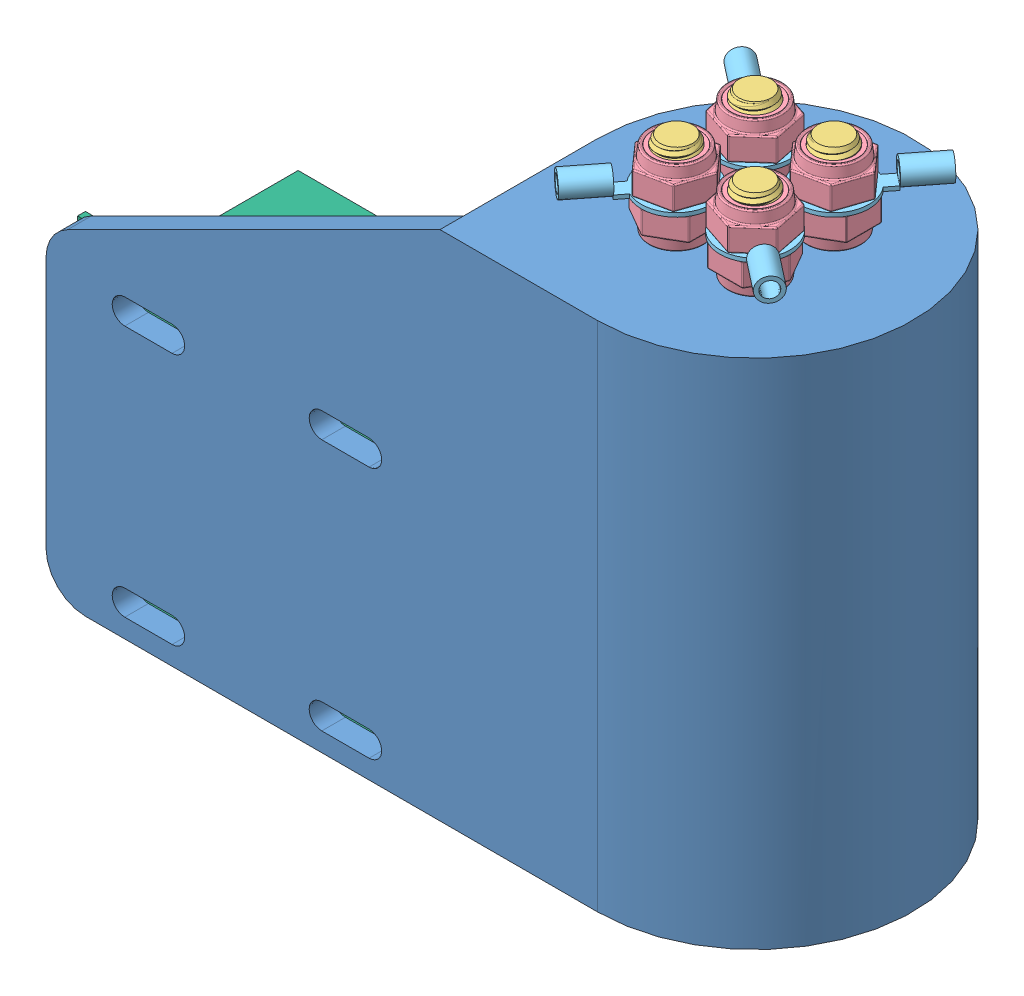
SolidWorks assembly Universal Tool Mount Assembly, configuration Default. Lengths in mm.
Overall size (90 76.45 40).
22 component instances, 6 part files, 13 mates.
Components (placement in the parent):
- Unversal Tool Mount-1: Unversal Tool Mount [Default] at (10.2776 2.9787 70.9053) size (90 65.26 40)
- 6.93mm OD x 11.5mm Length Spring-1: 6.93mm OD x 11.5mm Length Spring [94125K521] at (15.2776 53.7937 65.9053) x (0.975775 0 -0.218778) z (0.218778 0 0.975775) size (6.93 11.5 6.93)
- 5mm x 25mm Low Profile Socket Head Screw-1: 5mm x 25mm Low Profile Socket Head Screw [Default] at (15.2776 51.7287 65.9053) x (0 1 0) z (0.238136 0 0.971232) size (27.2 9.5 9.5)
- Nylon Insert Hex Locknut 5mm-1: Nylon Insert Hex Locknut 5mm [Default] at (15.2776 72.4787 65.9053) x (-0.999998 0 0.001945) z (0 -1 0) size (7.68 8.82 4.5)
- Nylon Insert Hex Locknut 5mm-2: Nylon Insert Hex Locknut 5mm [Default] at (15.2776 72.9787 65.9053) x (0.748413 0 -0.663233) z (0 1 0) size (7.68 8.82 4.5)
- Nylon Insert Hex Locknut 5mm-3: Nylon Insert Hex Locknut 5mm [Default] at (15.2776 72.9787 75.9053) x (0.663233 0 0.748413) z (0 1 0) size (7.68 8.82 4.5)
- Nylon Insert Hex Locknut 5mm-4: Nylon Insert Hex Locknut 5mm [Default] at (5.2776 72.9787 75.9053) x (-0.748413 0 0.663233) z (0 1 0) size (7.68 8.82 4.5)
- Nylon Insert Hex Locknut 5mm-5: Nylon Insert Hex Locknut 5mm [Default] at (5.2776 72.9787 65.9053) x (-0.663233 0 -0.748413) z (0 1 0) size (7.68 8.82 4.5)
- Nylon Insert Hex Locknut 5mm-6: Nylon Insert Hex Locknut 5mm [Default] at (15.2776 72.4787 75.9053) x (-0.001945 0 -0.999998) z (0 -1 0) size (7.68 8.82 4.5)
- Nylon Insert Hex Locknut 5mm-7: Nylon Insert Hex Locknut 5mm [Default] at (5.2776 72.4787 75.9053) x (0.999998 0 -0.001945) z (0 -1 0) size (7.68 8.82 4.5)
- Nylon Insert Hex Locknut 5mm-8: Nylon Insert Hex Locknut 5mm [Default] at (5.2776 72.4787 65.9053) x (0.001945 0 0.999998) z (0 -1 0) size (7.68 8.82 4.5)
- 5mm x 25mm Low Profile Socket Head Screw-2: 5mm x 25mm Low Profile Socket Head Screw [Default] at (15.2776 51.7287 75.9053) x (0 1 0) z (-0.971232 0 0.238136) size (27.2 9.5 9.5)
- 5mm x 25mm Low Profile Socket Head Screw-3: 5mm x 25mm Low Profile Socket Head Screw [Default] at (5.2776 51.7287 75.9053) x (0 1 0) z (-0.238136 0 -0.971232) size (27.2 9.5 9.5)
- 5mm x 25mm Low Profile Socket Head Screw-4: 5mm x 25mm Low Profile Socket Head Screw [Default] at (5.2776 51.7287 65.9053) x (0 1 0) z (0.971232 0 -0.238136) size (27.2 9.5 9.5)
- 6.93mm OD x 11.5mm Length Spring-2: 6.93mm OD x 11.5mm Length Spring [94125K521] at (15.2776 53.7937 75.9053) x (0.218778 0 0.975775) z (-0.975775 0 0.218778) size (6.93 11.5 6.93)
- 6.93mm OD x 11.5mm Length Spring-3: 6.93mm OD x 11.5mm Length Spring [94125K521] at (5.2776 53.7937 75.9053) x (-0.975775 0 0.218778) z (-0.218778 0 -0.975775) size (6.93 11.5 6.93)
- 6.93mm OD x 11.5mm Length Spring-4: 6.93mm OD x 11.5mm Length Spring [94125K521] at (5.2776 53.7937 65.9053) x (-0.218778 0 -0.975775) z (0.975775 0 -0.218778) size (6.93 11.5 6.93)
- M5 Ring Terminal-1: M5 Ring Terminal [Default] at (18.8721 72.4787 61.3074) x (-0.615897 0 0.787827) z (-0.787827 0 -0.615897) size (15.29 3 8.9)
- M5 Ring Terminal-2: M5 Ring Terminal [Default] at (19.8755 72.4787 79.4998) x (-0.787827 0 -0.615897) z (0.615897 0 -0.787827) size (15.29 3 8.9)
- M5 Ring Terminal-3: M5 Ring Terminal [Default] at (1.6831 72.4787 80.5032) x (0.615897 0 -0.787827) z (0.787827 0 0.615897) size (15.29 3 8.9)
- M5 Ring Terminal-4: M5 Ring Terminal [Default] at (0.6797 72.4787 62.3108) x (0.787827 0 0.615897) z (-0.615897 0 0.787827) size (15.29 3 8.9)
- Solenoid Lock-1: Solenoid Lock [Default] at (-58.7224 43.4787 87.9053) x (1 0 0) z (0 1 0) size (61 28 41)
Mates (geometry in assembly coordinates):
- Coincident1: coincident aligned: line of 6.93mm OD x 11.5mm Length Spring-1 through (15.2776 65.554 65.9053) axis (0 -1 0); axis of 5mm x 25mm Low Profile Socket Head Screw-1 through (15.2776 77.7837 65.9053) axis (0 -1 0)
- Distance1: distance = 0.315 mm aligned: plane of 6.93mm OD x 11.5mm Length Spring-1; plane of 5mm x 25mm Low Profile Socket Head Screw-1 through (12.8496 53.4787 66.5006) normal (0 1 0)
- Coincident4: coincident anti-aligned: axis of Unversal Tool Mount-1 through (15.2776 64.9787 65.9053) axis (0 1 0); axis of 5mm x 25mm Low Profile Socket Head Screw-1 through (15.2776 77.7837 65.9053) axis (0 -1 0)
- Coincident5: coincident aligned: axis of 5mm x 25mm Low Profile Socket Head Screw-1 through (15.2776 77.7837 65.9053) axis (0 -1 0); axis of Nylon Insert Hex Locknut 5mm-1 through (15.2776 72.4787 65.9053) axis (0 -1 0)
- Distance2: distance = 6 mm aligned: plane of Nylon Insert Hex Locknut 5mm-1 through (15.2776 72.4787 65.9053) normal (0 1 0); plane of 5mm x 25mm Low Profile Socket Head Screw-1 through (15.2776 78.4787 65.9053) normal (0 1 0)
- Coincident7: coincident anti-aligned: axis of 5mm x 25mm Low Profile Socket Head Screw-1 through (15.2776 77.7837 65.9053) axis (0 -1 0); axis of Nylon Insert Hex Locknut 5mm-2 through (15.2776 72.9787 65.9053) axis (0 1 0)
- Concentric1: concentric aligned: axis of Nylon Insert Hex Locknut 5mm-1 through (15.2776 72.4787 65.9053) axis (0 -1 0); cylinder of M5 Ring Terminal-1 through (15.2776 72.9787 65.9053) axis (0 -1 0) radius 2.5
- Coincident8: coincident anti-aligned: plane of Nylon Insert Hex Locknut 5mm-1 through (15.2776 72.4787 65.9053) normal (0 1 0); plane of M5 Ring Terminal-1 through (15.2776 72.4787 65.9053) normal (0 -1 0)
- Coincident9: coincident anti-aligned: plane of Nylon Insert Hex Locknut 5mm-2 through (15.2776 72.9787 65.9053) normal (0 -1 0); plane of M5 Ring Terminal-1 through (15.2776 72.9787 65.9053) normal (0 1 0)
- Coincident11: coincident anti-aligned: plane of Unversal Tool Mount-1 through (10.2776 2.9787 87.9053) normal (0 0 -1); plane of Solenoid Lock-1 through (-58.7224 43.4787 87.9053) normal (0 0 1)
- Coincident12: coincident anti-aligned: plane of Unversal Tool Mount-1 through (-9.7224 67.9787 70.9053) normal (-1 0 0); plane of Solenoid Lock-1 through (-9.7224 43.4787 86.9053) normal (1 0 0)
- Coincident14: coincident anti-aligned: plane of Unversal Tool Mount-1 through (10.2776 67.9787 70.9053) normal (0 1 0); plane of Nylon Insert Hex Locknut 5mm-1 through (15.2776 67.9787 65.9053) normal (0 -1 0)
- Width1: width anti-aligned: plane of Solenoid Lock-1 through (2.2776 27.9787 72.9053) normal (0 1 0); plane of Solenoid Lock-1 through (2.2776 17.9787 72.9053) normal (0 -1 0); plane of Unversal Tool Mount-1 through (30.2786 30.4787 80.9053) normal (0 -1 0); plane of Unversal Tool Mount-1 through (30.2786 15.4787 80.9053) normal (0 1 0)
